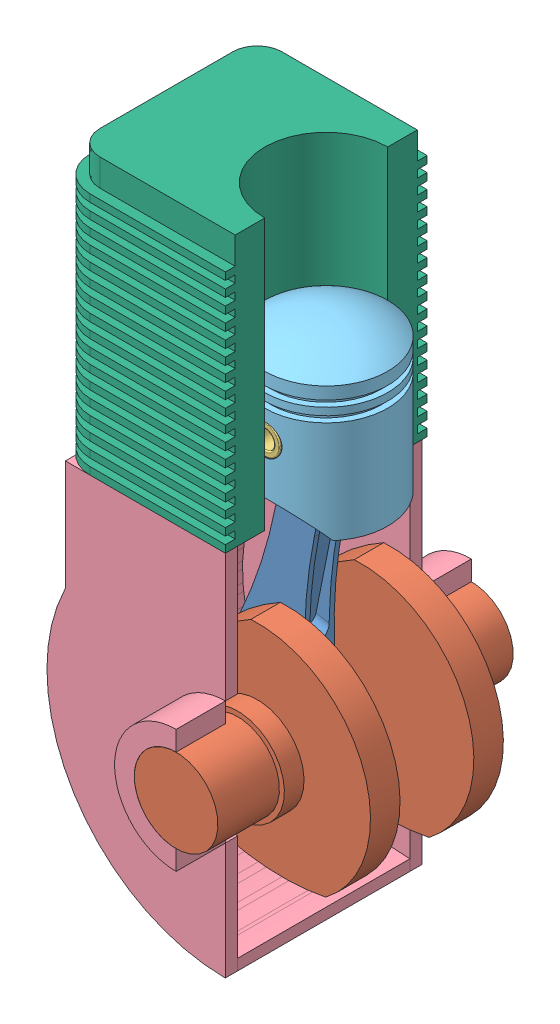
SolidWorks assembly engine assembly, configuration Default. Lengths in mm.
Overall size (131437.7 259892.96 120000).
6 component instances, 6 part files, 13 mates.
Components (placement in the parent):
- crank rod-1: crank rod [Default] at (8328.3292 2902.1906 4518.5681) x (0.980706 -0.195489 0) z (0 0 1) size (42000 160154.15 20000)
- crank shaft-1: crank shaft [Default] at (31787.0459 11544.4478 42518.5681) x (-0.34569 0.938349 0) z (0 0 1) size (88000 92000 120000)
- gudgen pin-1: gudgen pin [Default] at (31787.0459 120586.8906 -18481.4319) x (0 0 1) z (-0.957728 -0.287675 0) size (50000 12500 12500)
- lower case-1: lower case [Default] at (31787.0459 11544.4478 47518.5681) size (73073.29 149902.96 120000)
- piston-1: piston [Default] at (31787.0459 90086.8906 6518.5681) size (50000 62512.1 50000)
- upper case-1: upper case [Default] at (31787.0459 88544.4478 6518.5681) x (0 0 -1) z (1 0 0) size (82000 110000 69000)
Mates (geometry in assembly coordinates):
- Concentric2: concentric aligned: cylinder of crank shaft-1 through (31787.0459 11544.4478 67518.5681) axis (0 0 -1) radius 17000; cylinder of lower case-1 through (31787.0459 11544.4478 67518.5681) axis (0 0 -1) radius 17000
- Concentric3: concentric aligned: cylinder of crank shaft-1 through (31787.0459 11544.4478 -52481.4319) axis (0 0 1) radius 17000; cylinder of lower case-1 through (31787.0459 11544.4478 -52481.4319) axis (0 0 1) radius 17000
- Coincident2: coincident anti-aligned: plane of lower case-1 through (31787.0459 88544.4478 42518.5681) normal (0 1 0); plane of upper case-1 through (31787.0459 88544.4478 6518.5681) normal (0 -1 0)
- Coincident3: coincident anti-aligned: line of lower case-1 through (31787.0459 88544.4478 42518.5681) axis (0 0 1); line of upper case-1 through (31787.0459 88544.4478 47518.5681) axis (0 0 -1)
- Coincident4: coincident aligned: line of lower case-1 through (31787.0459 88544.4478 -27481.4319) axis (0 0 -1); line of upper case-1 through (31787.0459 88544.4478 -18481.4319) axis (0 0 -1)
- Concentric4: concentric anti-aligned: cylinder of crank rod-1 through (31787.0459 120586.8906 14518.5681) axis (0 0 -1) radius 6250; cylinder of piston-1 through (31787.0459 120586.8906 -18481.4319) axis (0 0 1) radius 6250
- Concentric16: concentric aligned: cylinder of crank rod-1 through (31787.0459 120586.8906 14518.5681) axis (0 0 -1) radius 6250; cylinder of gudgen pin-1 through (31787.0459 120586.8906 31518.5681) axis (0 0 -1) radius 6250
- Tangent3: tangent aligned: plane of gudgen pin-1 through (31787.0459 120586.8906 31518.5681) normal (0 0 1); cylinder of piston-1 through (31787.0459 152586.8906 6518.5681) axis (0 1 0) radius 25000
- Coincident7: coincident anti-aligned: plane of crank rod-1 through (31787.0459 120586.8906 -5481.4319) normal (0 0 -1); plane of piston-1 through (31787.0459 120586.8906 -5481.4319) normal (0 0 1)
- Concentric18: concentric anti-aligned: cylinder of piston-1 through (31787.0459 152586.8906 6518.5681) axis (0 1 0) radius 25000; cylinder of upper case-1 through (31787.0459 198544.4478 6518.5681) axis (0 -1 0) radius 25000
- Concentric19: concentric anti-aligned: cylinder of crank rod-1 through (8328.3292 2902.1906 14518.5681) axis (0 0 -1) radius 16000; cylinder of crank shaft-1 through (8328.3292 2902.1906 7518.5681) axis (0 0 1) radius 16000
- Coincident8: coincident aligned: plane of crank shaft-1 through (31787.0459 11544.4478 67518.5681) normal (0 0 1); plane of lower case-1 through (31787.0459 11544.4478 67518.5681) normal (0 0 1)
- Coincident9: coincident aligned: plane of lower case-1 through (31787.0459 11544.4478 47518.5681) normal (0 0 1); plane of upper case-1 through (31787.0459 91544.4478 47518.5681) normal (0 0 1)
